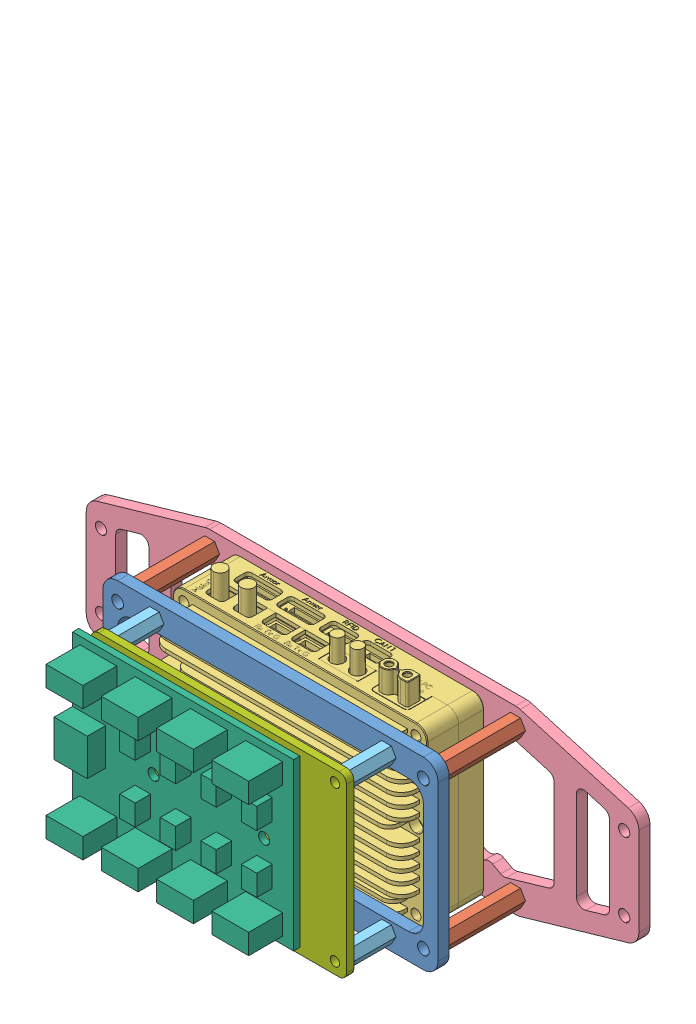
SolidWorks assembly 电管电容, configuration 默认. Lengths in mm.
Overall size (150 197.96 52.9).
13 component instances, 7 part files, 28 mates.
Components (placement in the parent):
- DP_电容管理模块安装板_1-1: DP_电容管理模块安装板_1 [默认] at origin size (91 50 3)
- DP_铝柱_M3x22-1: DP_铝柱_M3x22 [默认] at (41.5 -20 -11) size (5.43 4.7 22)
- DP_铝柱_M3x22-2: DP_铝柱_M3x22 [默认] at (-41.5 20 -11) size (5.43 4.7 22)
- DP_铝柱_M3x22-3: DP_铝柱_M3x22 [默认] at (41.5 20 -11) size (5.43 4.7 22)
- DP_铝柱_M3x22-4: DP_铝柱_M3x22 [默认] at (-41.5 -20 -11) size (5.43 4.7 22)
- DP_RoboMaster 电源模块 PM02 2020-2: DP_RoboMaster 电源模块 PM02 2020 [默认] at (-35.5843 22.8772 -14.2071) x (1 0 0) z (0 1 0) size (70.01 22.52 197.96)
- 步兵新的电管安放板-1: 步兵新的电管安放板 [默认] at (0 0 -25) size (150 49.05 3)
- M2.5X12-1: M2.5X12 [默认] at (31.5 -21 3) size (5.2 4.5 12)
- M2.5X12-2: M2.5X12 [默认] at (-31.5 21 3) size (5.2 4.5 12)
- M2.5X12-3: M2.5X12 [默认] at (-31.5 -21 3) size (5.2 4.5 12)
- M2.5X12-4: M2.5X12 [默认] at (31.5 21 3) size (5.2 4.5 12)
- 分电板_2-1: 分电板_2 [默认] at (-8.0215 0 17) x (0 1 0) z (0 0 1) size (45 60 10.9)
- 分电板放置板-1: 分电板放置板 [默认] at (0 0 15) size (69.25 48.25 2)
Mates (geometry in assembly coordinates):
- 重合3: coincident anti-aligned: plane of DP_电容管理模块安装板_1-1 through (0 0 0) normal (0 0 -1); plane of DP_铝柱_M3x22-1 through (41.5 -20 0) normal (0 0 1)
- 重合4: coincident aligned: plane of DP_铝柱_M3x22-2 through (-41.5 20 0) normal (0 0 1); plane of DP_铝柱_M3x22-3 through (41.5 20 0) normal (0 0 1)
- 重合5: coincident aligned: plane of DP_铝柱_M3x22-3 through (41.5 20 0) normal (0 0 1); plane of DP_铝柱_M3x22-4 through (-41.5 -20 0) normal (0 0 1)
- 重合6: coincident anti-aligned: plane of DP_电容管理模块安装板_1-1 through (0 0 0) normal (0 0 -1); plane of DP_铝柱_M3x22-3 through (41.5 20 0) normal (0 0 1)
- 同心8: concentric aligned: cylinder of DP_电容管理模块安装板_1-1 through (-41.5 -20 0) axis (0 0 1) radius 1.6; cylinder of DP_铝柱_M3x22-4 through (-41.5 -20 0) axis (0 0 1) radius 1.25
- 同心9: concentric aligned: cylinder of DP_电容管理模块安装板_1-1 through (-41.5 20 0) axis (0 0 1) radius 1.6; cylinder of DP_铝柱_M3x22-2 through (-41.5 20 0) axis (0 0 1) radius 1.25
- 同心10: concentric aligned: cylinder of DP_电容管理模块安装板_1-1 through (41.5 20 0) axis (0 0 1) radius 1.6; cylinder of DP_铝柱_M3x22-3 through (41.5 20 0) axis (0 0 1) radius 1.25
- 同心11: concentric aligned: cylinder of DP_电容管理模块安装板_1-1 through (41.5 -20 0) axis (0 0 1) radius 1.6; cylinder of DP_铝柱_M3x22-1 through (41.5 -20 0) axis (0 0 1) radius 1.25
- 同心15: concentric anti-aligned: cylinder of DP_电容管理模块安装板_1-1 through (31.5 21 0) axis (0 0 1) radius 1.3; cylinder of DP_RoboMaster 电源模块 PM02 2020-2 through (31.5 21 -14.5) axis (0 0 -1) radius 1.35
- 同心16: concentric anti-aligned: cylinder of DP_电容管理模块安装板_1-1 through (-31.5 21 0) axis (0 0 1) radius 1.3; cylinder of DP_RoboMaster 电源模块 PM02 2020-2 through (-31.5 21 -14.5) axis (0 0 -1) radius 1.35
- 重合8: coincident: plane of DP_电容管理模块安装板_1-1 through (0 0 0) normal (0 0 -1); line of DP_RoboMaster 电源模块 PM02 2020-2 through (28.5 -15.5 0) axis (-1 0 0)
- 重合10: coincident anti-aligned: plane of DP_铝柱_M3x22-4 through (-41.5 -20 -22) normal (0 0 -1); plane of 步兵新的电管安放板-1 through (0 0 -22) normal (0 0 1)
- 同心19: concentric anti-aligned: cylinder of DP_电容管理模块安装板_1-1 through (-41.5 -20 0) axis (0 0 1) radius 1.6; cylinder of 步兵新的电管安放板-1 through (-41.5 -20 -22) axis (0 0 -1) radius 1.525
- 同心20: concentric anti-aligned: cylinder of DP_电容管理模块安装板_1-1 through (41.5 -20 0) axis (0 0 1) radius 1.6; cylinder of 步兵新的电管安放板-1 through (41.5 -20 -22) axis (0 0 -1) radius 1.525
- 重合11: coincident aligned: plane of M2.5X12-1 through (31.5 -21 15) normal (0 0 1); plane of M2.5X12-2 through (-31.5 21 15) normal (0 0 1)
- 重合12: coincident aligned: plane of M2.5X12-2 through (-31.5 21 15) normal (0 0 1); plane of M2.5X12-3 through (-31.5 -21 15) normal (0 0 1)
- 重合13: coincident aligned: plane of M2.5X12-3 through (-31.5 -21 15) normal (0 0 1); plane of M2.5X12-4 through (31.5 21 15) normal (0 0 1)
- 同心21: concentric aligned: cylinder of DP_电容管理模块安装板_1-1 through (31.5 21 0) axis (0 0 1) radius 1.3; cylinder of M2.5X12-4 through (31.5 21 15) axis (0 0 1) radius 1.025
- 重合14: coincident anti-aligned: plane of DP_电容管理模块安装板_1-1 through (0 0 3) normal (0 0 1); plane of M2.5X12-1 through (31.5 -21 3) normal (0 0 -1)
- 同心22: concentric aligned: cylinder of DP_电容管理模块安装板_1-1 through (31.5 -21 0) axis (0 0 1) radius 1.3; cylinder of M2.5X12-1 through (31.5 -21 15) axis (0 0 1) radius 1.025
- 同心23: concentric aligned: cylinder of DP_电容管理模块安装板_1-1 through (-31.5 21 0) axis (0 0 1) radius 1.3; cylinder of M2.5X12-2 through (-31.5 21 15) axis (0 0 1) radius 1.025
- 同心24: concentric aligned: cylinder of DP_电容管理模块安装板_1-1 through (-31.5 -21 0) axis (0 0 1) radius 1.3; cylinder of M2.5X12-3 through (-31.5 -21 15) axis (0 0 1) radius 1.025
- 重合15: coincident anti-aligned: plane of M2.5X12-1 through (31.5 -21 15) normal (0 0 1); plane of 分电板放置板-1 through (0 0 15) normal (0 0 -1)
- 同心25: concentric aligned: cylinder of M2.5X12-1 through (31.5 -21 15) axis (0 0 1) radius 1.025; circle of 分电板放置板-1
- 同心26: concentric anti-aligned: cylinder of M2.5X12-3 through (-31.5 -21 15) axis (0 0 1) radius 1.025; cylinder of 分电板放置板-1 through (-31.5 -21 17) axis (0 0 -1) radius 1.275
- 重合16: coincident anti-aligned: plane of 分电板_2-1 through (-7.9293 0.1556 17) normal (0 0 -1); plane of 分电板放置板-1 through (0 0 17) normal (0 0 1)
- 槽口1: slot aligned: cylinder of ? through (14.0702 0 18.7) axis (0 0 -1) radius 1.5; cylinder of 分电板放置板-1 through (16.5 0 17) axis (0 0 -1) radius 1.55; cylinder of 分电板放置板-1 through (8.5 0 17) axis (0 0 -1) radius 1.55
- 槽口2: slot: plane of 分电板放置板-1 through (-16.5 -1.55 17) normal (0 1 0); cylinder of 分电板_2-1 through (-15.9291 0.2122 18.7) axis (0 0 -1) radius 1.5; cylinder of 分电板放置板-1 through (-16.5 0 17) axis (0 0 -1) radius 1.55
